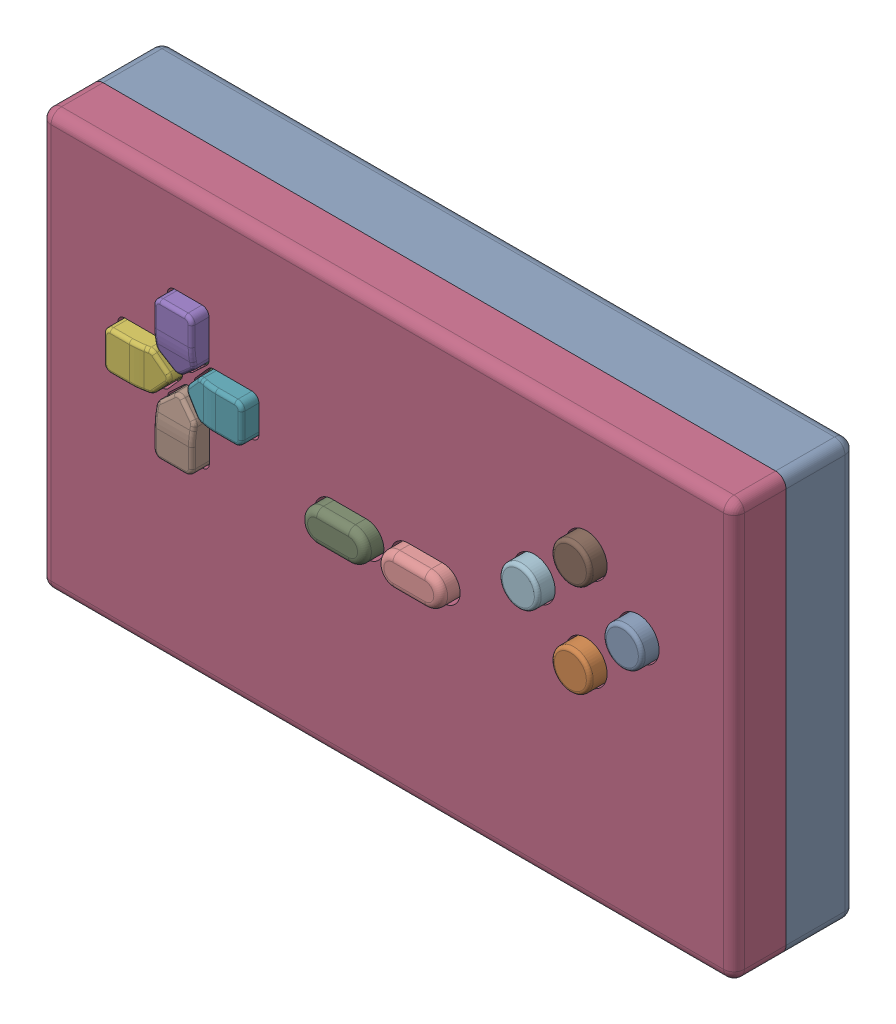
SolidWorks assembly 控制器装配体, configuration Default. Lengths in mm.
Overall size (100 60 19.8).
14 component instances, 7 part files, 33 mates.
Components (placement in the parent):
- 壳体下-1: 壳体下 [Default] at origin size (100 60 12)
- PCB2-1: PCB2 [Default] at (-0.1 11.55 3) size (33.02 12.7 1.6)
- 按键PCB-1: 按键PCB [默认] at (0 0 8) size (85 48 6.8)
- 壳体上-1: 壳体上 [Default] at (0 0 17.5) x (-1 0 0) z (0 0 -1) size (100 60 8.4)
- 按键1-1: 按键1 [Default] at (-28.7293 13.3848 14.3) size (7 9.46 5.5)
- 按键1-2: 按键1 [Default] at (-35.3848 6.6707 14.3) x (0 1 0) z (0 0 1) size (7 9.46 5.5)
- 按键1-3: 按键1 [Default] at (-22.0152 6.7293 14.3) x (0 -1 0) z (0 0 1) size (7 9.46 5.5)
- 按键1-4: 按键1 [Default] at (-28.6707 0.0152 14.3) x (-1 0 0) z (0 0 1) size (7 9.46 5.5)
- 按键2-1: 按键2 [Default] at (-5.5988 -0.5 14.3) size (10.2 5.6 5.5)
- 按键2-2: 按键2 [Default] at (5.3979 -0.5 14.3) size (10.2 5.6 5.5)
- 按键3-1: 按键3 [Default] at (28.7 13.4 14.3) x (0.718066 0.695975 0) z (0 0 1) size (6.6 6.6 5.5)
- 按键3-2: 按键3 [Default] at (21.2 6.7 14.3) x (0.835113 -0.550078 0) z (0 0 1) size (6.6 6.6 5.5)
- 按键3-3: 按键3 [Default] at (36.2 6.7 14.3) x (0.726906 -0.686737 0) z (0 0 1) size (6.6 6.6 5.5)
- 按键3-4: 按键3 [Default] at (28.7 0 14.3) x (0.408462 0.912775 0) z (0 0 1) size (6.6 6.6 5.5)
Mates (geometry in assembly coordinates):
- 重合1: coincident anti-aligned: plane of 壳体下-1 through (0 0 3) normal (0 0 1); plane of PCB2-1 through (-0.1 11.55 3) normal (0 0 -1)
- 重合2: coincident anti-aligned: plane of 壳体下-1 through (-16.61 17.9 5) normal (0 -1 0); plane of PCB2-1 through (16.41 17.9 4.6) normal (0 1 0)
- 重合3: coincident anti-aligned: plane of 壳体下-1 through (-16.61 17.9 5) normal (1 0 0); plane of PCB2-1 through (-16.61 5.2 4.6) normal (-1 0 0)
- 同心1: concentric anti-aligned: cylinder of 壳体下-1 through (-39 20.5 10.5) axis (0 0 -1) radius 1.2; cylinder of 按键PCB-1 through (-39 20.5 4.6) axis (0 0 1) radius 1.25
- 同心2: concentric anti-aligned: cylinder of 壳体下-1 through (39 -20.5 10.5) axis (0 0 -1) radius 1.2; cylinder of 按键PCB-1 through (39 -20.5 4.6) axis (0 0 1) radius 1.25
- 重合4: coincident anti-aligned: plane of 壳体下-1 through (39 -20.5 8) normal (0 0 1); plane of 按键PCB-1 through (0 0 8) normal (0 0 -1)
- 重合5: coincident aligned: plane of 壳体下-1 through (50 30 2) normal (0 1 0); plane of 壳体上-1 through (-50 30 15.5) normal (0 1 0)
- 重合6: coincident aligned: plane of 壳体下-1 through (-50 -30 2) normal (-1 0 0); plane of 壳体上-1 through (-50 -30 15.5) normal (-1 0 0)
- 重合7: coincident anti-aligned: plane of 壳体下-1 through (0 0 10) normal (0 0 1); plane of 壳体上-1 through (0 0 10) normal (0 0 -1)
- 重合8: coincident anti-aligned: plane of 按键PCB-1 through (-28.7 13.4 14.8) normal (0 0 1); plane of 按键1-1 through (-28.7293 15.1848 14.8) normal (0 0 -1)
- 重合10: distance = 0.2 mm anti-aligned: plane of 按键1-1 through (-26.9212 16.6753 19.8) normal (0 1 0); plane of 壳体上-1 through (-30.7212 16.8753 7.5) normal (0 -1 0)
- 重合11: distance = 0.2 mm anti-aligned: plane of 按键1-1 through (-25.9212 10.525 19.8) normal (1 0 0); plane of 壳体上-1 through (-25.7212 10.4087 7.5) normal (-1 0 0)
- 重合12: coincident anti-aligned: plane of 按键PCB-1 through (-36.2 6.7 14.8) normal (0 0 1); plane of 按键1-2 through (-37.1848 6.6707 14.8) normal (0 0 -1)
- 距离4: distance = 0.2 mm anti-aligned: plane of 按键1-2 through (-38.6753 8.4788 19.8) normal (-1 0 0); plane of 壳体上-1 through (-38.8753 4.6788 7.5) normal (1 0 0)
- 距离5: distance = 0.2 mm anti-aligned: plane of 按键1-2 through (-32.525 9.4788 19.8) normal (0 1 0); plane of 壳体上-1 through (-32.4087 9.6788 7.5) normal (0 -1 0)
- 重合13: coincident anti-aligned: plane of 按键PCB-1 through (-21.2 6.7 14.8) normal (0 0 1); plane of 按键1-3 through (-20.2152 6.7293 14.8) normal (0 0 -1)
- 距离6: distance = 0.2 mm anti-aligned: plane of 按键1-3 through (-18.7247 4.9212 19.8) normal (1 0 0); plane of 壳体上-1 through (-18.5247 8.7212 7.5) normal (-1 0 0)
- 距离7: distance = 0.2 mm anti-aligned: plane of 按键1-3 through (-24.875 3.9212 19.8) normal (0 -1 0); plane of 壳体上-1 through (-24.9913 3.7212 7.5) normal (0 1 0)
- 重合15: coincident anti-aligned: plane of 按键PCB-1 through (-28.7 0 14.8) normal (0 0 1); plane of 按键1-4 through (-28.6707 -1.7848 14.8) normal (0 0 -1)
- 距离8: distance = 0.2 mm anti-aligned: plane of 按键1-4 through (-30.4788 -3.2753 19.8) normal (0 -1 0); plane of 壳体上-1 through (-26.6788 -3.4753 7.5) normal (0 1 0)
- 距离9: distance = 0.2 mm anti-aligned: plane of 按键1-4 through (-31.4788 2.875 19.8) normal (-1 0 0); plane of 壳体上-1 through (-31.6788 2.9913 7.5) normal (1 0 0)
- 重合16: coincident anti-aligned: plane of 按键PCB-1 through (-5.5 -0.5 14.8) normal (0 0 1); plane of 按键2-1 through (-5.5988 -0.5 14.8) normal (0 0 -1)
- 重合17: distance = 0.2 mm anti-aligned: plane of 按键2-1 through (-3.2988 1.8 19.8) normal (0 1 0); plane of 壳体上-1 through (-8 2 7.5) normal (0 -1 0)
- 重合18: coincident anti-aligned: plane of 按键PCB-1 through (5.5 -0.5 14.8) normal (0 0 1); plane of 按键2-2 through (5.3979 -0.5 14.8) normal (0 0 -1)
- 距离11: distance = 0.2 mm anti-aligned: plane of 按键2-2 through (7.6979 1.8 19.8) normal (0 1 0); plane of 壳体上-1 through (0 2 7.5) normal (0 -1 0)
- 同心7: concentric anti-aligned: circle of 按键PCB-1; cylinder of 按键3-1 through (28.7 13.4 14.8) axis (0 0 -1) radius 2
- 重合19: coincident anti-aligned: plane of 按键PCB-1 through (28.7 13.4 14.8) normal (0 0 1); plane of 按键3-1 through (28.7 13.4 14.8) normal (0 0 -1)
- 同心8: concentric aligned: cylinder of 按键PCB-1 through (21.2 6.7 14.8) axis (0 0 -1) radius 1.8; cylinder of 按键3-2 through (21.2 6.7 14.8) axis (0 0 -1) radius 2
- 重合20: coincident anti-aligned: plane of 按键PCB-1 through (21.2 6.7 14.8) normal (0 0 1); plane of 按键3-2 through (21.2 6.7 14.8) normal (0 0 -1)
- 同心9: concentric aligned: cylinder of 按键PCB-1 through (36.2 6.7 14.8) axis (0 0 -1) radius 1.8; cylinder of 按键3-3 through (36.2 6.7 14.8) axis (0 0 -1) radius 2
- 重合21: coincident anti-aligned: plane of 按键PCB-1 through (36.2 6.7 14.8) normal (0 0 1); plane of 按键3-3 through (36.2 6.7 14.8) normal (0 0 -1)
- 同心10: concentric anti-aligned: circle of 按键PCB-1; cylinder of 按键3-4 through (28.7 0 14.8) axis (0 0 -1) radius 2
- 重合22: coincident anti-aligned: plane of 按键PCB-1 through (28.7 0 14.8) normal (0 0 1); plane of 按键3-4 through (28.7 0 14.8) normal (0 0 -1)
